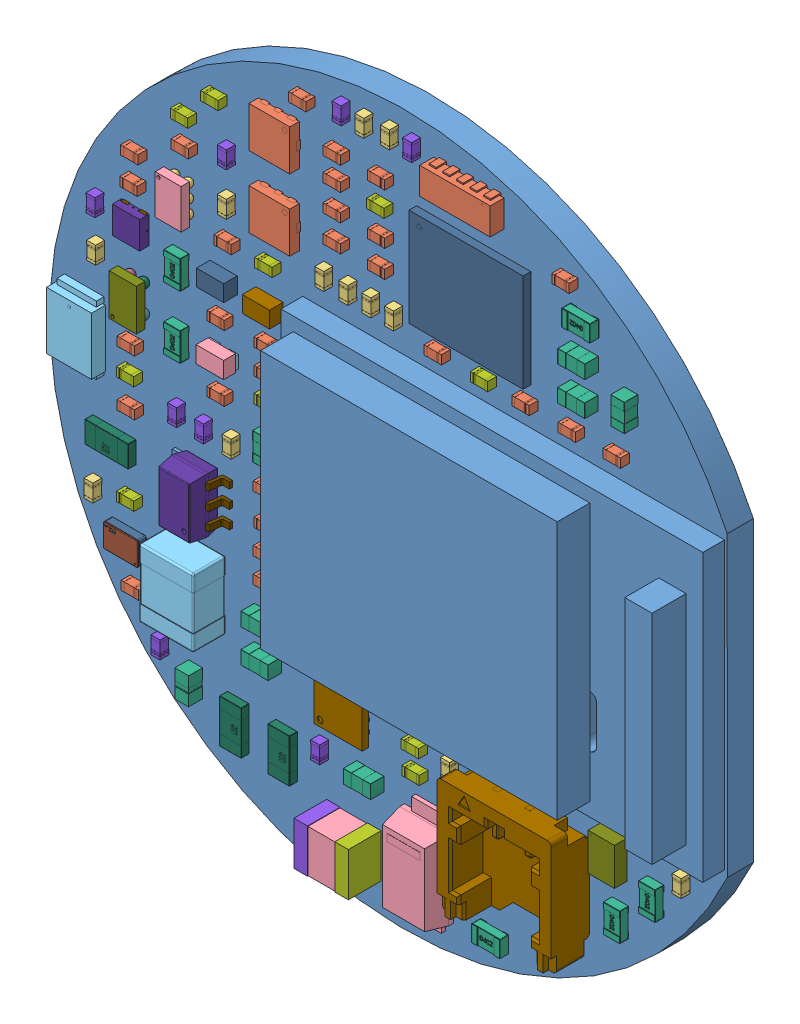
SolidWorks assembly Biocoin_v1.3, configuration Default. Lengths in mm.
Overall size (24.9 26.1 4.91).
226 component instances, 48 part files, 0 mates.
Components (placement in the parent):
- Biocoin_v1.3.step-1: Biocoin_v1.3.step [Default] at origin size (24.9 26.1 4.91)
  - Board.step-1: Board.step [Default] at origin size (24.9 26.1 0.96)
    - Open CASCADE STEP translator 7.5 1.1.1.step-1: Open CASCADE STEP translator 7.5 1.1.1.step [Default] at (0 0 -0.9603) size (24.9 26.1 0.96)
  - R31.step-1: R31.step [Default] at origin size (0.64 0.33 0.33)
    - 6017375920.step-1: 6017375920.step [Default] at (6.6294 18.7198 0) x (-1 0 0) z (0 0 1) size (0.64 0.33 0.33)
  - R30.step-1: R30.step [Default] at origin size (0.33 0.64 0.33)
    - 6073967344.step-1: 6073967344.step [Default] at (1.8034 16.0528 0) x (0 -1 0) z (0 0 1) size (0.64 0.33 0.33)
  - Q4.step-1: Q4.step [Default] at origin size (1.04 0.61 0.54)
    - 6073960464.step-1: 6073960464.step [Default] at (6.3754 14.9606 0) size (1.04 0.61 0.54)
      - Body.step-1: Body.step [Default] at (0 0 0.1) size (1.01 0.61 0.44)
      - Pins.step-1: Pins.step [Default] at origin size (1.04 0.51 0.1)
  - RSENSE.step-1: RSENSE.step [Default] at origin size (0.6 1.04 0.34)
    - User Library-0402R.step-1: User Library-0402R.step [Default] at (4.7752 14.6813 0) x (0 1 0) z (1 0 0) size (1.04 0.34 0.6)
  - R29.step-1: R29.step [Default] at origin size (0.64 0.33 0.33)
    - 6017375920.step-1: 6017375920.step [Default] at (6.3754 16.1798 0) x (-1 0 0) z (0 0 1) size (0.64 0.33 0.33)
  - R28.step-1: R28.step [Default] at origin size (0.64 0.33 0.33)
    - 6073960624.step-1: 6073960624.step [Default] at (8.1026 14.4018 0) size (0.64 0.33 0.33)
  - R27.step-1: R27.step [Default] at origin size (0.64 0.33 0.33)
    - 6017375920.step-1: 6017375920.step [Default] at (8.1026 16.2052 0) x (-1 0 0) z (0 0 1) size (0.64 0.33 0.33)
  - R26.step-1: R26.step [Default] at origin size (0.6 1.04 0.34)
    - User Library-0402R.step-1: User Library-0402R.step [Default] at (4.7752 16.9753 0) x (0 1 0) z (1 0 0) size (1.04 0.34 0.6)
  - R25.step-1: R25.step [Default] at origin size (0.33 0.64 0.33)
    - 6073967344.step-1: 6073967344.step [Default] at (6.7818 12.3698 0) x (0 -1 0) z (0 0 1) size (0.64 0.33 0.33)
  - R24.step-1: R24.step [Default] at origin size (0.64 0.33 0.33)
    - 6017375920.step-1: 6017375920.step [Default] at (6.3754 13.7668 0) x (-1 0 0) z (0 0 1) size (0.64 0.33 0.33)
  - R23.step-1: R23.step [Default] at origin size (0.33 0.64 0.33)
    - 6073963104.step-1: 6073963104.step [Default] at (5.7658 12.3444 0) x (0 1 0) z (0 0 1) size (0.64 0.33 0.33)
  - R19.step-1: R19.step [Default] at origin size (0.64 0.33 0.33)
    - 6017375920.step-1: 6017375920.step [Default] at (3.0734 11.684 0) x (-1 0 0) z (0 0 1) size (0.64 0.33 0.33)
  - R12.step-1: R12.step [Default] at origin size (0.64 0.33 0.33)
    - 6073960624.step-1: 6073960624.step [Default] at (3.048 12.7254 0) size (0.64 0.33 0.33)
  - Q3.step-1: Q3.step [Default] at origin size (1 0.6 0.53)
    - 6073964224.step-1: 6073964224.step [Default] at (8.0558 17.399 0.03) x (1 0 0) z (0 -1 0) size (1 0.53 0.6)
  - Q2.step-1: Q2.step [Default] at origin size (1 0.6 0.53)
    - 6017376720.step-1: 6017376720.step [Default] at (6.3714 17.399 0.03) x (-1 0 0) z (0 1 0) size (1 0.53 0.6)
  - IC3.step-1: IC3.step [Default] at origin size (1 1.52 0.67)
    - 6073961504.step-1: 6073961504.step [Default] at (3.302 15.3924 0) x (0 1 0) z (0 0 1) size (1.52 1 0.67)
      - A1.step-1: A1.step [Default] at (-0.5 0.25 0.175) size (0.35 0.35 0.35)
      - A2.step-1: A2.step [Default] at (0 0.25 0.175) size (0.35 0.35 0.35)
      - A3.step-1: A3.step [Default] at (0.5 0.25 0.175) size (0.35 0.35 0.35)
      - B1.step-1: B1.step [Default] at (-0.5 -0.25 0.175) size (0.35 0.35 0.35)
      - B3.step-1: B3.step [Default] at (0.5 -0.25 0.175) size (0.35 0.35 0.35)
      - Body-0.step-1: Body-0.step [Default] at origin size (1.52 1 0.32)
  - IC2.step-1: IC2.step [Default] at origin size (2.1 2 1.1)
    - 6073963824.step-1: 6073963824.step [Default] at (5.6134 10.3124 0) x (-1 0 0) z (0 0 1) size (2.1 2 1.1)
      - Body-1.step-1: Body-1.step [Default] at origin size (1.25 2 1.05)
      - PinsArrayL.step-1: PinsArrayL.step [Default] at origin size (0.42 1.53 0.56)
      - PinsArrayR.step-1: PinsArrayR.step [Default] at origin size (0.42 1.53 0.56)
  - C39.step-1: C39.step [Default] at origin size (0.64 0.33 0.33)
    - 6017375920.step-1: 6017375920.step [Default] at (8.1026 15.2908 0) x (-1 0 0) z (0 0 1) size (0.64 0.33 0.33)
  - C38.step-1: C38.step [Default] at origin size (0.33 0.64 0.33)
    - 6073963104.step-1: 6073963104.step [Default] at (4.7752 12.3698 0) x (0 1 0) z (0 0 1) size (0.64 0.33 0.33)
  - C37.step-1: C37.step [Default] at origin size (0.64 0.33 0.33)
    - 6017375920.step-1: 6017375920.step [Default] at (3.0758 13.7179 0) x (-1 0 0) z (0 0 1) size (0.64 0.33 0.33)
  - U4.step-1: U4.step [Default] at origin size (1.5 1.5 0.4)
    - TLV8542RUGR.step-1: TLV8542RUGR.step [Default] at (8.4328 20.4216 0.0128) x (0 -1 0) z (-1 0 0) size (1.5 0.4 1.5)
  - R22.step-1: R22.step [Default] at origin size (0.33 0.64 0.33)
    - 6073967344.step-1: 6073967344.step [Default] at (10.1854 19.408 0) x (0 -1 0) z (0 0 1) size (0.64 0.33 0.33)
  - R21.step-1: R21.step [Default] at origin size (0.64 0.33 0.33)
    - 6017375920.step-1: 6017375920.step [Default] at (10.6426 20.7518 0) x (-1 0 0) z (0 0 1) size (0.64 0.33 0.33)
  - C34.step-1: C34.step [Default] at origin size (0.33 0.64 0.33)
    - 6073967344.step-1: 6073967344.step [Default] at (11.0744 19.408 0) x (0 -1 0) z (0 0 1) size (0.64 0.33 0.33)
  - C33.step-1: C33.step [Default] at origin size (0.64 0.33 0.33)
    - 6017375920.step-1: 6017375920.step [Default] at (12.2682 20.7518 0) x (-1 0 0) z (0 0 1) size (0.64 0.33 0.33)
  - L4.step-1: L4.step [Default] at origin size (0.64 0.33 0.33)
    - 6073960624.step-1: 6073960624.step [Default] at (8.128 18.7452 0) size (0.64 0.33 0.33)
  - R20.step-1: R20.step [Default] at origin size (0.33 0.64 0.33)
    - 6073967344.step-1: 6073967344.step [Default] at (1.7018 8.4328 0) x (0 -1 0) z (0 0 1) size (0.64 0.33 0.33)
  - R16.step-1: R16.step [Default] at origin size (0.64 0.33 0.33)
    - 6073960624.step-1: 6073960624.step [Default] at (5.0292 21.9456 0) size (0.64 0.33 0.33)
  - R15.step-1: R15.step [Default] at origin size (0.64 0.33 0.33)
    - 6017375920.step-1: 6017375920.step [Default] at (3.2004 19.8628 0) x (-1 0 0) z (0 0 1) size (0.64 0.33 0.33)
  - Q1.step-1: Q1.step [Default] at origin size (0.95 1.45 0.62)
    - 6073963584.step-1: 6073963584.step [Default] at (4.9276 19.3802 0) size (0.95 1.45 0.62)
      - Array.step-1: Array.step [Default] at origin size (0.81 1.31 0.31)
      - Body-2.step-1: Body-2.step [Default] at origin size (0.95 1.45 0.32)
  - L1.step-1: L1.step [Default] at origin size (2 2.5 1.2)
    - DFE252012F-100M=P2.step-1: DFE252012F-100M=P2.step [Default] at (5.4356 7.3152 0.0128) x (0 -1 0) z (-1 0 0) size (2.5 1.2 2)
  - C30.step-1: C30.step [Default] at origin size (0.64 0.33 0.33)
    - 6017375920.step-1: 6017375920.step [Default] at (3.2258 6.0198 0) x (-1 0 0) z (0 0 1) size (0.64 0.33 0.33)
  - C24.step-1: C24.step [Default] at origin size (1.05 0.51 0.51)
    - User Library-SMD Ceramic Capacitors_0402 (1005)_BB.step-1: User Library-SMD Ceramic Capacitors_0402 (1005)_BB.step [Default] at (7.972 6.1 0) x (-1 0 0) z (0 0 1) size (1.05 0.51 0.51)
  - J5.step-1: J5.step [Default] at origin size (3.6 11.7 1.9)
    - 503480-2000.step-1: 503480-2000.step [Default] at (1.5748 12.9794 -0.9731) x (0 1 0) z (-1 0 0) size (11.7 1.9 3.6)
      - Open CASCADE STEP translator 7.5 1.35.1.1.step-1: Open CASCADE STEP translator 7.5 1.35.1.1.step [Default] at origin size (11.7 1.9 3.6)
      - Open CASCADE STEP translator 7.5 1.35.1.2.step-1: Open CASCADE STEP translator 7.5 1.35.1.2.step [Default] at origin
  - R9.step-1: R9.step [Default] at origin size (0.64 0.33 0.33)
    - 6017375920.step-1: 6017375920.step [Default] at (5.0546 20.9804 0) x (-1 0 0) z (0 0 1) size (0.64 0.33 0.33)
  - R10.step-1: R10.step [Default] at origin size (0.33 0.64 0.33)
    - 6073967344.step-1: 6073967344.step [Default] at (6.604 19.9136 0) x (0 -1 0) z (0 0 1) size (0.64 0.33 0.33)
  - C28.step-1: C28.step [Default] at origin size (0.64 0.33 0.33)
    - 6017375920.step-1: 6017375920.step [Default] at (3.175 18.8468 0) x (-1 0 0) z (0 0 1) size (0.64 0.33 0.33)
  - IC1.step-1: IC1.step [Default] at origin size (1.77 1.77 0.5)
    - 6073966224.step-1: 6073966224.step [Default] at (11.049 6.223 0) x (0 1 0) z (0 0 1) size (1.77 1.77 0.5)
      - Array-3.step-1: Array-3.step [Default] at origin size (1.47 1.47 0.27)
      - Body-4.step-1: Body-4.step [Default] at origin size (1.77 1.77 0.23)
  - U2.step-1: U2.step [Default] at origin size (1.5 1.5 0.4)
    - TLV8542RUGR.step-1: TLV8542RUGR.step [Default] at (8.4328 23.0378 0.0128) x (0 -1 0) z (-1 0 0) size (1.5 0.4 1.5)
  - R18.step-1: R18.step [Default] at origin size (0.64 0.33 0.33)
    - 6073960624.step-1: 6073960624.step [Default] at (3.048 8.763 0) size (0.64 0.33 0.33)
  - R17.step-1: R17.step [Default] at origin size (0.33 0.64 0.33)
    - 6073967344.step-1: 6073967344.step [Default] at (14.8082 6.096 0) x (0 -1 0) z (0 0 1) size (0.64 0.33 0.33)
  - IC6.step-1: IC6.step [Default] at origin size (1.27 0.87 0.51)
    - IC_Maxim_Integrated_MAX17291ANT+T_eec.step-1: IC_Maxim_Integrated_MAX17291ANT+T_eec.step [Default] at (3.048 7.4676 0) x (-1 0 0) z (0 0 1) size (1.27 0.87 0.51)
      - 1.step-1: 1.step [Default] at (0 0 0.17) size (1.27 0.87 0.27)
      - 2.step-1: 2.step [Default] at (0 0 0.46) size (1.27 0.87 0.04)
      - 3.step-1: 3.step [Default] at (0 0 0.135) size (1.07 0.67 0.27)
      - Maxim Integrated Logo 1 - 1.step-1: Maxim Integrated Logo 1 - 1.step [Default] at (2.4226 -1.4739 0.401) size (1.14 0.74 0.11)
      - Maxim Integrated Logo 1.step-1: Maxim Integrated Logo 1.step [Default] at (1.1635 -2.318 0.401) size (0.12 0.12 0.1)
  - C36.step-1: C36.step [Default] at origin size (1.6 0.8 0.3)
    - SW3dPS-0603 SMD Capacitor.step-1: SW3dPS-0603 SMD Capacitor.step [Default] at (2.3369 10.2108 0) x (-1 0 0) z (0 1 0) size (1.6 0.3 0.8)
  - U8.step-1: U8.step [Default] at origin size (0.97 1.37 0.69)
    - 6073963184.step-1: 6073963184.step [Default] at (20.9042 6.477 0) size (0.97 1.37 0.69)
  - C32.step-1: C32.step [Default] at origin size (0.33 0.64 0.33)
    - 6073967344.step-1: 6073967344.step [Default] at (23.3172 6.6548 0) x (0 -1 0) z (0 0 1) size (0.64 0.33 0.33)
  - C31.step-1: C31.step [Default] at origin size (1.05 0.51 0.51)
    - User Library-SMD Ceramic Capacitors_0402 (1005)_BB.step-1: User Library-SMD Ceramic Capacitors_0402 (1005)_BB.step [Default] at (7.972 7.3192 0) x (-1 0 0) z (0 0 1) size (1.05 0.51 0.51)
  - U6.step-1: U6.step [Default] at origin size (1 1 0.36)
    - DQN0004A.step-1: DQN0004A.step [Default] at (3.1263 17.5361 0.0328) x (-1 0 0) z (0 1 0) size (1 0.36 1)
      - MOLD-SNB04A.step-1: MOLD-SNB04A.step [Default] at origin size (1 0.34 1)
      - FRAME-SNB04A.step-1: FRAME-SNB04A.step [Default] at (0 -0.02 0) size (1 0.11 1)
  - R14.step-1: R14.step [Default] at origin size (0.64 0.33 0.33)
    - 6073960624.step-1: 6073960624.step [Default] at (13.5128 6.1214 0) size (0.64 0.33 0.33)
  - C29.step-1: C29.step [Default] at origin size (0.33 0.64 0.33)
    - 6073963104.step-1: 6073963104.step [Default] at (1.778 17.5514 0) x (0 1 0) z (0 0 1) size (0.64 0.33 0.33)
  - R13.step-1: R13.step [Default] at origin size (1.04 0.6 0.34)
    - User Library-0402R.step-1: User Library-0402R.step [Default] at (16.3069 1.397 0) x (1 0 0) z (0 -1 0) size (1.04 0.34 0.6)
  - R8.step-1: R8.step [Default] at origin size (0.64 0.33 0.33)
    - 6017375920.step-1: 6017375920.step [Default] at (10.6426 22.7076 0) x (-1 0 0) z (0 0 1) size (0.64 0.33 0.33)
  - M2.step-1: M2.step [Default] at origin size (15.5 10.5 2.05)
    - MDBT50Q 3D Drawing_20180620_RGB8421504.step-1: MDBT50Q 3D Drawing_20180620_RGB8421504.step [Default] at (17.0122 12.9858 0.0128) x (0 -1 0) z (-1 0 0) size (10.5 2.05 15.5)
  - R11.step-1: R11.step [Default] at origin size (0.33 0.64 0.33)
    - 6073963104.step-1: 6073963104.step [Default] at (4.1656 4.6736 0) x (0 1 0) z (0 0 1) size (0.64 0.33 0.33)
  - C27.step-1: C27.step [Default] at origin size (0.64 0.33 0.33)
    - 6017375920.step-1: 6017375920.step [Default] at (12.2682 21.7424 0) x (-1 0 0) z (0 0 1) size (0.64 0.33 0.33)
  - C26.step-1: C26.step [Default] at origin size (0.64 0.33 0.33)
    - 6073960624.step-1: 6073960624.step [Default] at (6.1468 23.0632 0) size (0.64 0.33 0.33)
  - C25.step-1: C25.step [Default] at origin size (0.33 0.64 0.33)
    - 6073967344.step-1: 6073967344.step [Default] at (12.5984 25.1206 0) x (0 -1 0) z (0 0 1) size (0.64 0.33 0.33)
  - U3.step-1: U3.step [Default] at origin size (2.59 1.09 0.56)
    - 6073961184.step-1: 6073961184.step [Default] at (15.4003 24.6078 0) x (0 -1 0) z (0 0 1) size (1.09 2.59 0.56)
  - C13.step-1: C13.step [Default] at origin size (0.33 0.64 0.33)
    - 6073963104.step-1: 6073963104.step [Default] at (6.604 21.4884 0) x (0 1 0) z (0 0 1) size (0.64 0.33 0.33)
  - R7.step-1: R7.step [Default] at origin size (0.64 0.33 0.33)
    - 6017375920.step-1: 6017375920.step [Default] at (10.6426 21.7424 0) x (-1 0 0) z (0 0 1) size (0.64 0.33 0.33)
  - R5.step-1: R5.step [Default] at origin size (0.64 0.33 0.33)
    - 6017375920.step-1: 6017375920.step [Default] at (10.6426 23.5712 0) x (-1 0 0) z (0 0 1) size (0.64 0.33 0.33)
  - C12.step-1: C12.step [Default] at origin size (0.64 0.33 0.33)
    - 6017375920.step-1: 6017375920.step [Default] at (12.2682 23.5966 0) x (-1 0 0) z (0 0 1) size (0.64 0.33 0.33)
  - J2.step-1: J2.step [Default] at origin size (1.83 3.81 1)
    - 21120928.step-1: 21120928.step [Default] at (14.0716 2.4257 0) size (0.25 0.25 0.25)
      - Extruded.step-1: Extruded.step [Default] at origin size (0.25 0.25 0.25)
    - SDO_SOD-123FL_ONS.step-1: SDO_SOD-123FL_ONS.step [Default] at (13.9447 2.5526 0) x (0 1 0) z (0 0 1) size (3.81 1.83 1)
  - S1.step-1: S1.step [Default] at origin size (1.65 2.5 0.56)
    - 6017376320.step-1: 6017376320.step [Default] at (1.2192 13.3096 0) x (0 -1 0) z (0 0 1) size (2.5 1.65 0.56)
  - D1.step-1: D1.step [Default] at origin size (0.51 0.99 0.51)
    - 6073960224.step-1: 6073960224.step [Default] at (5.3086 4.064 0) x (0 1 0) z (0 0 1) size (0.99 0.51 0.51)
  - R6.step-1: R6.step [Default] at origin size (0.64 0.33 0.33)
    - 6073960624.step-1: 6073960624.step [Default] at (13.5128 6.9342 0) size (0.64 0.33 0.33)
  - L3.step-1: L3.step [Default] at origin size (2 1.6 1.2)
    - 6073968144.step-1: 6073968144.step [Default] at (11.1252 1.8542 0) x (-1 0 0) z (0 0 1) size (2 1.6 1.2)
      - term1.step-1: term1.step [Default] at (-1 -0.8 0) size (0.5 1.6 1.2)
      - term2.step-1: term2.step [Default] at (0.5 -0.8 0) size (0.5 1.6 1.2)
      - Body.step-1: Body.step [Default] at (-0.5 -0.784 0.012) size (1 1.57 1.18)
  - C23.step-1: C23.step [Default] at origin size (0.8 1.6 0.3)
    - SW3dPS-0603 SMD Capacitor.step-1: SW3dPS-0603 SMD Capacitor.step [Default] at (6.8834 3.4799 0) x (0 -1 0) z (-1 0 0) size (1.6 0.3 0.8)
  - C22.step-1: C22.step [Default] at origin size (0.8 1.6 0.3)
    - SW3dPS-0603 SMD Capacitor.step-1: SW3dPS-0603 SMD Capacitor.step [Default] at (8.6614 3.4799 0) x (0 -1 0) z (-1 0 0) size (1.6 0.3 0.8)
  - C21.step-1: C21.step [Default] at origin size (0.33 0.64 0.33)
    - 6073963104.step-1: 6073963104.step [Default] at (10.033 4.2672 0) x (0 1 0) z (0 0 1) size (0.64 0.33 0.33)
  - C20.step-1: C20.step [Default] at origin size (0.64 0.33 0.33)
    - 6073960624.step-1: 6073960624.step [Default] at (13.5382 5.2832 0) size (0.64 0.33 0.33)
  - C19.step-1: C19.step [Default] at origin size (1.05 0.51 0.51)
    - User Library-SMD Ceramic Capacitors_0402 (1005)_BB.step-1: User Library-SMD Ceramic Capacitors_0402 (1005)_BB.step [Default] at (11.7348 4.195 0) x (-1 0 0) z (0 0 1) size (1.05 0.51 0.51)
  - J1.step-1: J1.step [Default] at origin size (4.2 4.3 1.45)
    - 6073967584.step-1: 6073967584.step [Default] at (17.7292 4.699 0) x (1 0 0) z (0 -1 0) size (4.2 1.45 4.3)
  - U1.step-1: U1.step [Default] at origin size (4.19 3.61 0.56)
    - 6073961024.step-1: 6073961024.step [Default] at (15.8088 21.6742 0) size (4.19 3.61 0.56)
  - RTIA1.step-1: RTIA1.step [Default] at origin size (1.04 0.6 0.34)
    - User Library-0402R.step-1: User Library-0402R.step [Default] at (19.6151 22.6394 0) x (-1 0 0) z (0 1 0) size (1.04 0.34 0.6)
  - RCAL1.step-1: RCAL1.step [Default] at origin size (0.33 0.64 0.33)
    - 6073967344.step-1: 6073967344.step [Default] at (11.6586 25.019 0) x (0 -1 0) z (0 0 1) size (0.64 0.33 0.33)
  - R4.step-1: R4.step [Default] at origin size (0.64 0.33 0.33)
    - 6017375920.step-1: 6017375920.step [Default] at (9.3726 24.638 0) x (-1 0 0) z (0 0 1) size (0.64 0.33 0.33)
  - R3.step-1: R3.step [Default] at origin size (0.6 1.04 0.34)
    - User Library-0402R.step-1: User Library-0402R.step [Default] at (22.225 5.6133 0) x (0 -1 0) z (-1 0 0) size (1.04 0.34 0.6)
  - R2.step-1: R2.step [Default] at origin size (0.6 1.04 0.34)
    - User Library-0402R.step-1: User Library-0402R.step [Default] at (20.9296 4.2925 0) x (0 -1 0) z (-1 0 0) size (1.04 0.34 0.6)
  - R1.step-1: R1.step [Default] at origin size (0.64 0.33 0.33)
    - 6017375920.step-1: 6017375920.step [Default] at (8.1026 10.4648 0) x (-1 0 0) z (0 0 1) size (0.64 0.33 0.33)
  - CTIA1.step-1: CTIA1.step [Default] at origin size (1.05 0.51 0.51)
    - User Library-SMD Ceramic Capacitors_0402 (1005)_BB.step-1: User Library-SMD Ceramic Capacitors_0402 (1005)_BB.step [Default] at (19.6152 21.5004 0) x (-1 0 0) z (0 0 1) size (1.05 0.51 0.51)
  - CLPF1.step-1: CLPF1.step [Default] at origin size (0.33 0.64 0.33)
    - 6073963104.step-1: 6073963104.step [Default] at (10.8204 24.9936 0) x (0 1 0) z (0 0 1) size (0.64 0.33 0.33)
  - C18.step-1: C18.step [Default] at origin size (0.64 0.33 0.33)
    - 6017375920.step-1: 6017375920.step [Default] at (8.0772 8.636 0) x (-1 0 0) z (0 0 1) size (0.64 0.33 0.33)
  - C17.step-1: C17.step [Default] at origin size (0.64 0.33 0.33)
    - 6017375920.step-1: 6017375920.step [Default] at (8.0772 11.6078 0) x (-1 0 0) z (0 0 1) size (0.64 0.33 0.33)
  - C16.step-1: C16.step [Default] at origin size (0.51 1.05 0.51)
    - User Library-SMD Ceramic Capacitors_0402 (1005)_BB.step-1: User Library-SMD Ceramic Capacitors_0402 (1005)_BB.step [Default] at (8.1574 13.0302 0) x (0 1 0) z (0 0 1) size (1.05 0.51 0.51)
  - C15.step-1: C15.step [Default] at origin size (0.64 0.33 0.33)
    - 6017375920.step-1: 6017375920.step [Default] at (8.0772 9.5504 0) x (-1 0 0) z (0 0 1) size (0.64 0.33 0.33)
  - C14.step-1: C14.step [Default] at origin size (0.64 0.33 0.33)
    - 6017375920.step-1: 6017375920.step [Default] at (20.932 19.0754 0) x (-1 0 0) z (0 0 1) size (0.64 0.33 0.33)
  - C11.step-1: C11.step [Default] at origin size (1.05 0.51 0.51)
    - User Library-SMD Ceramic Capacitors_0402 (1005)_BB.step-1: User Library-SMD Ceramic Capacitors_0402 (1005)_BB.step [Default] at (19.6088 20.2558 0) x (-1 0 0) z (0 0 1) size (1.05 0.51 0.51)
  - C10.step-1: C10.step [Default] at origin size (0.64 0.33 0.33)
    - 6073960624.step-1: 6073960624.step [Default] at (12.2428 22.6822 0) size (0.64 0.33 0.33)
  - C9.step-1: C9.step [Default] at origin size (0.51 1.05 0.51)
    - User Library-SMD Ceramic Capacitors_0402 (1005)_BB.step-1: User Library-SMD Ceramic Capacitors_0402 (1005)_BB.step [Default] at (21.3146 20.7534 0) x (0 1 0) z (0 0 1) size (1.05 0.51 0.51)
  - C8.step-1: C8.step [Default] at origin size (0.64 0.33 0.33)
    - 6017375920.step-1: 6017375920.step [Default] at (19.05 23.6982 0) x (-1 0 0) z (0 0 1) size (0.64 0.33 0.33)
  - C7.step-1: C7.step [Default] at origin size (0.64 0.33 0.33)
    - 6017375920.step-1: 6017375920.step [Default] at (19.281 19.0754 0) x (-1 0 0) z (0 0 1) size (0.64 0.33 0.33)
  - C6.step-1: C6.step [Default] at origin size (0.64 0.33 0.33)
    - 6073960624.step-1: 6073960624.step [Default] at (16.0552 19.0754 0) size (0.64 0.33 0.33)
  - C5.step-1: C5.step [Default] at origin size (0.64 0.33 0.33)
    - 6017375920.step-1: 6017375920.step [Default] at (14.3534 19.0754 0) x (-1 0 0) z (0 0 1) size (0.64 0.33 0.33)
  - C4.step-1: C4.step [Default] at origin size (0.33 0.64 0.33)
    - 6073963104.step-1: 6073963104.step [Default] at (13.4112 25.1206 0) x (0 1 0) z (0 0 1) size (0.64 0.33 0.33)
  - C3.step-1: C3.step [Default] at origin size (0.33 0.64 0.33)
    - 6073967344.step-1: 6073967344.step [Default] at (11.9126 19.4334 0) x (0 -1 0) z (0 0 1) size (0.64 0.33 0.33)
  - C2.step-1: C2.step [Default] at origin size (0.33 0.64 0.33)
    - 6073967344.step-1: 6073967344.step [Default] at (12.7508 19.4334 0) x (0 -1 0) z (0 0 1) size (0.64 0.33 0.33)
  - C1.step-1: C1.step [Default] at origin size (0.64 0.33 0.33)
    - 6017375920.step-1: 6017375920.step [Default] at (17.5792 19.0754 0) x (-1 0 0) z (0 0 1) size (0.64 0.33 0.33)
